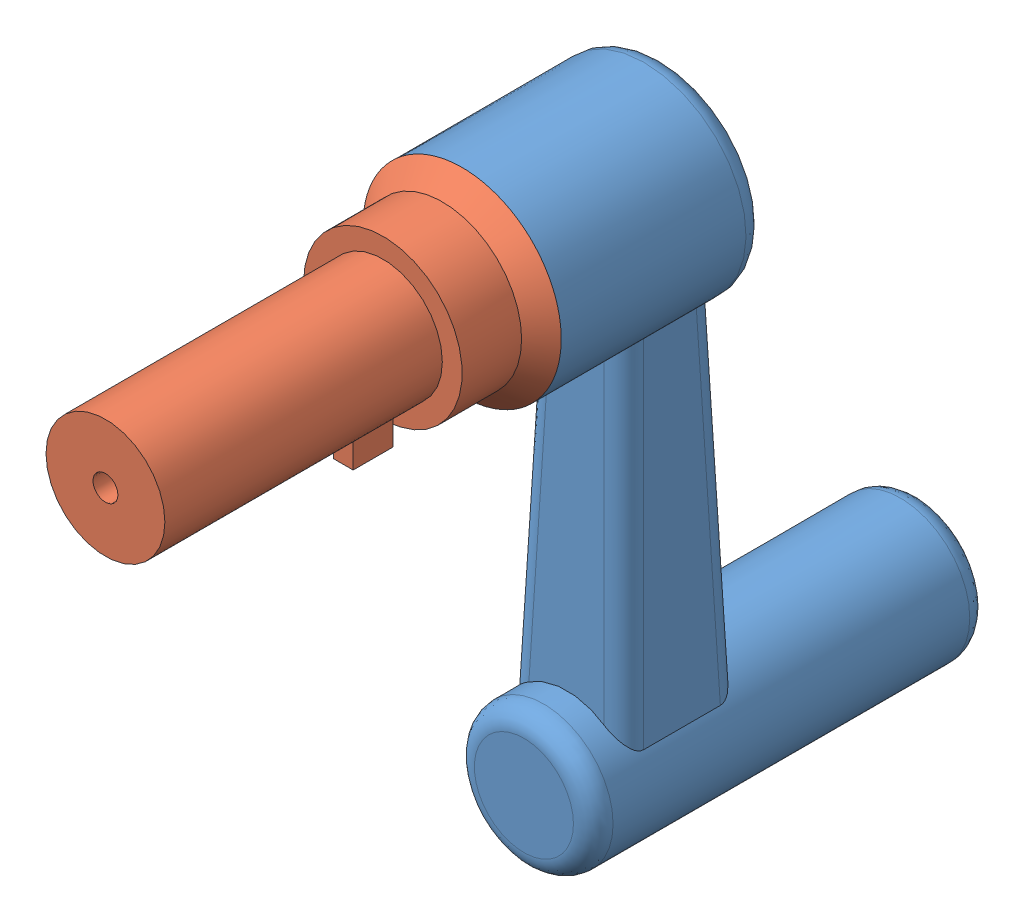
SolidWorks assembly Throttle Assem, configuration Default. Lengths in mm.
Overall size (50 162.5 205.58).
2 component instances, 2 part files, 3 mates.
Components (placement in the parent):
- Throttle-1: Throttle [Default] at (62.9986 64.9505 136.9834) size (50 162.5 115.58)
- Throttle Shaft-1: Throttle Shaft [Default] at (62.9986 184.9505 262.5624) x (-1 0 0) z (0 0 1) size (50 50 115)
Mates (geometry in assembly coordinates):
- Concentric1: concentric aligned: cylinder of Throttle-1 through (62.9986 184.9505 227.5624) axis (0 0 1) radius 7.5; cylinder of Throttle Shaft-1 through (62.9986 184.9505 227.5624) axis (0 0 1) radius 7.5
- Coincident1: coincident anti-aligned: plane of Throttle-1 through (62.9986 184.9505 227.5624) normal (0 0 1); plane of Throttle Shaft-1 through (62.9986 184.9505 227.5624) normal (0 0 -1)
- Coincident2: coincident anti-aligned: plane of Throttle-1 through (62.9986 64.9505 136.9834) normal (1 0 0); plane of Throttle Shaft-1
